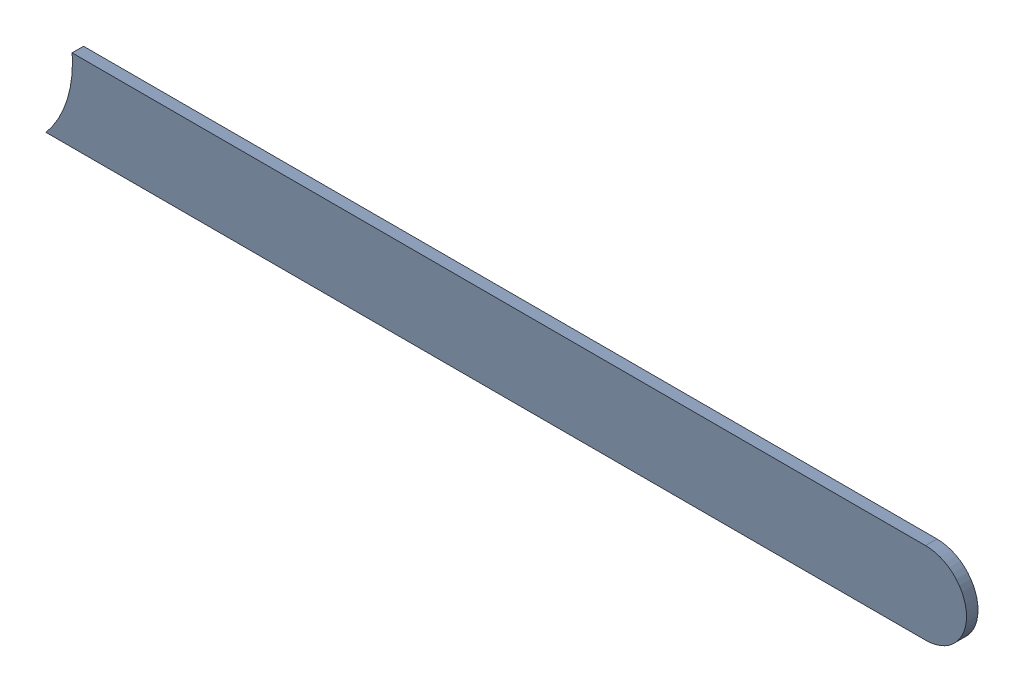
SolidWorks assembly Track (19.2mm,28.1mm)(22.1mm,28.1mm) on Top Layer, configuration Predeterminado. Lengths in mm.
Overall size (2.85 0.25 0.04).
2 component instances, 1 part files, 0 mates.
Components (placement in the parent):
- Track (19.2mm,28.1mm)(22.1mm,28.1mm) on Top Layer-1-1: Track (19.2mm,28.1mm)(22.1mm,28.1mm) on Top Layer-1 [Predeterminado] at (-68.317 -44.187 -0.0457) size (2.85 0.25 0.04)
  - Track (19.2mm,28.1mm)(22.1mm,28.1mm) on Top Layer-Part-1-1: Track (19.2mm,28.1mm)(22.1mm,28.1mm) on Top Layer-Part-1 [Predeterminado] at origin size (2.85 0.25 0.04)
